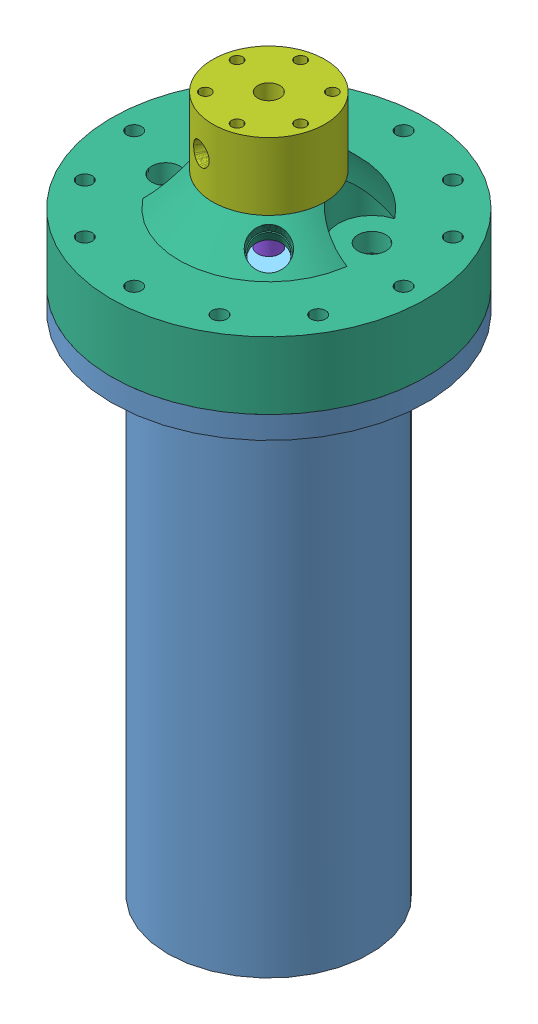
SolidWorks assembly APL1_firstEngineTest3, configuration config 2. Lengths in mm.
Overall size (251.45 393.7 251.45).
9 component instances, 9 part files, 21 mates.
Components (placement in the parent):
- APL1_OuterChamberCasing-1: APL1_OuterChamberCasing [Default] at origin
- APL1_ablativeInsert-1: APL1_ablativeInsert [Default] at (0 -6.35 0) x (0.966975 0 -0.25487) z (0.25487 0 0.966975)
- APL1_graphiteInsert-1: APL1_graphiteInsert [Default] at (0 -158.75 0) x (0.995497 0 -0.094792) z (0.094792 0 0.995497)
- APL1_LowerInjectorPlate3-1: APL1_LowerInjectorPlate3 [Default] at (0 -6.35 0) x (-0.707107 0 0.707107) z (-0.707107 0 -0.707107)
- APL1_TopInjectorPlate3-1: APL1_TopInjectorPlate3 [Default] at (0 12.7 0) x (-0.965926 0 0.258819) z (-0.258819 0 -0.965926)
- APL1_dome3-1: APL1_dome3 [Default] x (0.707107 0 0.707107) z (-0.707107 0 0.707107)
- APL1_ignitor2-1: APL1_ignitor2 [Default] at (0 57.15 0) x (-0.258819 0 0.965926) z (-0.965926 0 -0.258819)
- APL1_ignitorCore3-1: APL1_ignitorCore3 [Default] at (0 -6.35 0) x (0.973548 0 -0.228482) z (0.228482 0 0.973548)
- APL1_dowel3_1-1: APL1_dowel3_1 [Default] at (-31.4309 -3.175 31.4309) x (0.879237 0 0.476385) z (-0.476385 0 0.879237) size (3.17 28.57 3.17)
Mates (geometry in assembly coordinates):
- Concentric5: concentric aligned: cylinder of APL1_OuterChamberCasing-1 through (0 0 0) axis (0 1 0) radius 51.1302; cylinder of APL1_ablativeInsert-1 through (0 -6.35 0) axis (0 1 0) radius 51.1302
- Concentric6: concentric aligned: cylinder of APL1_OuterChamberCasing-1 through (0 0 0) axis (0 1 0) radius 51.1302; cylinder of APL1_graphiteInsert-1 through (0 -158.75 0) axis (0 1 0) radius 51.1302
- Coincident7: coincident anti-aligned: plane of APL1_ablativeInsert-1 through (-36.8418 -158.75 9.7106) normal (0 -1 0); plane of APL1_graphiteInsert-1 through (-44.5786 -158.75 4.2448) normal (0 1 0)
- Coincident8: coordinate: point of APL1_OuterChamberCasing-1
- Coincident9: coincident aligned: plane of APL1_OuterChamberCasing-1 through (-51.1302 -6.35 0) normal (0 1 0); plane of APL1_ablativeInsert-1 through (-36.8418 -6.35 9.7106) normal (0 1 0)
- Concentric7: concentric anti-aligned: cylinder of APL1_OuterChamberCasing-1 through (0 0 0) axis (0 1 0) radius 88.9; cylinder of APL1_LowerInjectorPlate3-1 through (0 -6.35 0) axis (0 -1 0) radius 57.15
- Coincident10: coincident anti-aligned: plane of APL1_OuterChamberCasing-1 through (-51.1302 -6.35 0) normal (0 1 0); plane of APL1_LowerInjectorPlate3-1 through (4.4901 -6.35 -4.4901) normal (0 -1 0)
- Concentric8: concentric anti-aligned: cylinder of APL1_OuterChamberCasing-1 through (0 0 0) axis (0 1 0) radius 88.9; cylinder of APL1_dome3-1 through (0 0 0) axis (0 -1 0) radius 88.9
- Concentric10: concentric anti-aligned: cylinder of APL1_OuterChamberCasing-1 through (0 0 0) axis (0 1 0) radius 88.9; cylinder of APL1_ignitor2-1 through (0 57.15 0) axis (0 -1 0) radius 31.75
- Concentric11: concentric anti-aligned: cylinder of APL1_OuterChamberCasing-1 through (0 0 0) axis (0 1 0) radius 88.9; cylinder of APL1_TopInjectorPlate3-1 through (0 12.7 0) axis (0 -1 0) radius 50.8
- Coincident11: coincident anti-aligned: plane of APL1_dome3-1 through (-22.4506 57.15 -22.4506) normal (0 1 0); plane of APL1_ignitor2-1 through (1.6435 57.15 -6.1336) normal (0 -1 0)
- Coincident12: coincident anti-aligned: plane of APL1_OuterChamberCasing-1 through (-57.15 0 0) normal (0 1 0); plane of APL1_dome3-1 through (-39.558 0 -39.558) normal (0 -1 0)
- Coincident13: coincident anti-aligned: plane of APL1_TopInjectorPlate3-1 through (0 19.05 0) normal (0 1 0); plane of APL1_dome3-1 through (-22.4506 19.05 -22.4506) normal (0 -1 0)
- Concentric12: concentric anti-aligned: cylinder of APL1_OuterChamberCasing-1 through (0 0 0) axis (0 1 0) radius 88.9; cylinder of APL1_ignitorCore3-1 through (0 -6.35 0) axis (0 -1 0) radius 12.7
- Coincident14: coincident anti-aligned: plane of APL1_TopInjectorPlate3-1 through (0 12.7 0) normal (0 -1 0); plane of APL1_ignitorCore3-1 through (-12.3641 12.7 2.9017) normal (0 1 0)
- Concentric13: concentric aligned: cylinder of APL1_OuterChamberCasing-1 through (-65.9911 0 38.1) axis (0 1 0) radius 4.2164; cylinder of APL1_dome3-1 through (-65.9911 38.1 38.1) axis (0 1 0) radius 4.2164
- Concentric15: concentric aligned: cylinder of APL1_dome3-1 through (-6.574 57.15 -24.5345) axis (0 1 0) radius 3.175; cylinder of APL1_ignitor2-1 through (-6.574 95.25 -24.5345) axis (0 1 0) radius 3.175
- Concentric16: concentric anti-aligned: cylinder of APL1_LowerInjectorPlate3-1 through (-31.4309 0 31.4309) axis (0 1 0) radius 1.5875; cylinder of APL1_dowel3_1-1 through (-31.4309 25.4 31.4309) axis (0 -1 0) radius 1.5875
- Concentric17: concentric anti-aligned: cylinder of APL1_TopInjectorPlate3-1 through (-31.4309 19.05 31.4309) axis (0 1 0) radius 1.5875; cylinder of APL1_dowel3_1-1 through (-31.4309 25.4 31.4309) axis (0 -1 0) radius 1.5875
- Concentric18: concentric aligned: cylinder of APL1_dome3-1 through (-31.4309 19.05 31.4309) axis (0 -1 0) radius 1.5875; cylinder of APL1_dowel3_1-1 through (-31.4309 25.4 31.4309) axis (0 -1 0) radius 1.5875
- Coincident16: coincident anti-aligned: circle of APL1_dome3-1; plane of APL1_dowel3_1-1 through (-31.4309 25.4 31.4309) normal (0 1 0)
